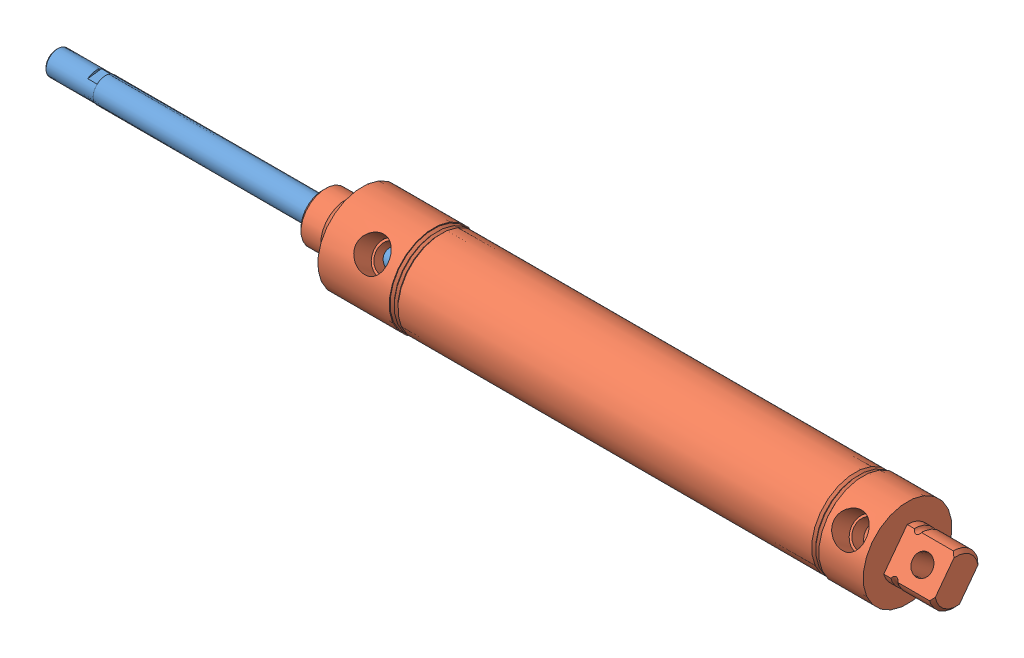
SolidWorks assembly Assem7, configuration Default. Lengths in mm.
Overall size (288.51 39.83 39.83).
2 component instances, 2 part files, 2 mates.
Components (placement in the parent):
- Part13-1: Part13 [Default] at (-789.4221 91.7606 159.0815) size (172.97 26.99 26.99)
- mainbody-1: mainbody [Default] at (25.6908 91.7606 159.0815) x (1 0 0) z (0 0.600371 0.799721) size (203.2 28.45 28.45)
Mates (geometry in assembly coordinates):
- Concentric1: concentric: cylinder of Part13-1 through (103.7017 91.7606 159.0815) axis (-1 0 0) radius 3.9624; cylinder of mainbody-1 through (28.7388 91.7606 159.0815) axis (-1 0 0) radius 3.9624
- LimitDistance1: limit distance = 99.789 mm: plane of Part13-1 through (116.4017 91.7606 159.0815) normal (1 0 0); plane of mainbody-1 through (216.1908 98.083 154.3351) normal (1 0 0)
